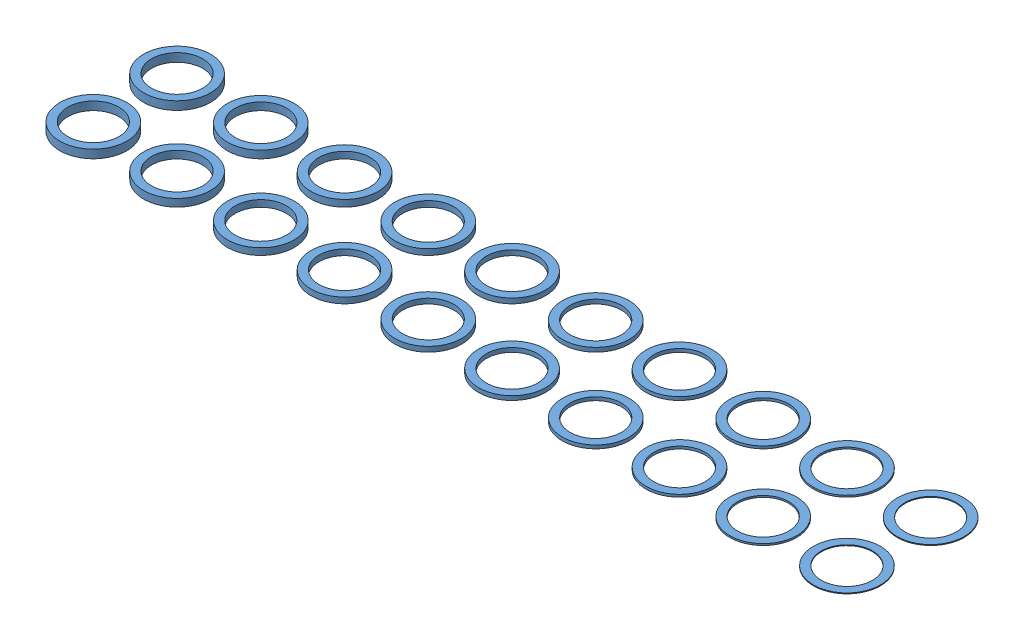
SolidWorks assembly Antrieb-Passscheibe, configuration Standard. Lengths in mm.
Overall size (98 1 18).
20 component instances, 1 part files, 3 mates.
Components (placement in the parent):
- Antrieb-Passscheibe-1: Antrieb-Passscheibe [T=1] x (1 0 0) z (0 -1 0) size (8 8 1)
- Antrieb-Passscheibe-2: Antrieb-Passscheibe [T=0,9] at (10 0 0) x (1 0 0) z (0 -1 0) size (8 8 0.9)
- Antrieb-Passscheibe-3: Antrieb-Passscheibe [T=0,8] at (20 0 0) x (1 0 0) z (0 -1 0) size (8 8 0.8)
- Antrieb-Passscheibe-4: Antrieb-Passscheibe [T=0,7] at (30 0 0) x (1 0 0) z (0 -1 0) size (8 8 0.7)
- Antrieb-Passscheibe-5: Antrieb-Passscheibe [T=0,6] at (40 0 0) x (1 0 0) z (0 -1 0) size (8 8 0.6)
- Antrieb-Passscheibe-6: Antrieb-Passscheibe [T=0,5] at (50 0 0) x (1 0 0) z (0 -1 0) size (8 8 0.5)
- Antrieb-Passscheibe-7: Antrieb-Passscheibe [T=0,4] at (60 0 0) x (1 0 0) z (0 -1 0) size (8 8 0.4)
- Antrieb-Passscheibe-8: Antrieb-Passscheibe [T=0,3] at (70 0 0) x (1 0 0) z (0 -1 0) size (8 8 0.3)
- Antrieb-Passscheibe-9: Antrieb-Passscheibe [T=0,2] at (80 0 0) x (1 0 0) z (0 -1 0) size (8 8 0.2)
- Antrieb-Passscheibe-10: Antrieb-Passscheibe [T=0,1] at (90 0 0) x (1 0 0) z (0 -1 0) size (8 8 0.1)
- Antrieb-Passscheibe-11: Antrieb-Passscheibe [T=0,6] at (40 0 -10) x (1 0 0) z (0 -1 0) size (8 8 0.6)
- Antrieb-Passscheibe-12: Antrieb-Passscheibe [T=0,4] at (60 0 -10) x (1 0 0) z (0 -1 0) size (8 8 0.4)
- Antrieb-Passscheibe-13: Antrieb-Passscheibe [T=0,5] at (50 0 -10) x (1 0 0) z (0 -1 0) size (8 8 0.5)
- Antrieb-Passscheibe-14: Antrieb-Passscheibe [T=0,1] at (90 0 -10) x (1 0 0) z (0 -1 0) size (8 8 0.1)
- Antrieb-Passscheibe-15: Antrieb-Passscheibe [T=0,2] at (80 0 -10) x (1 0 0) z (0 -1 0) size (8 8 0.2)
- Antrieb-Passscheibe-16: Antrieb-Passscheibe [T=0,3] at (70 0 -10) x (1 0 0) z (0 -1 0) size (8 8 0.3)
- Antrieb-Passscheibe-17: Antrieb-Passscheibe [T=0,7] at (30 0 -10) x (1 0 0) z (0 -1 0) size (8 8 0.7)
- Antrieb-Passscheibe-18: Antrieb-Passscheibe [T=0,8] at (20 0 -10) x (1 0 0) z (0 -1 0) size (8 8 0.8)
- Antrieb-Passscheibe-19: Antrieb-Passscheibe [T=1] at (0 0 -10) x (1 0 0) z (0 -1 0) size (8 8 1)
- Antrieb-Passscheibe-20: Antrieb-Passscheibe [T=0,9] at (10 0 -10) x (1 0 0) z (0 -1 0) size (8 8 0.9)
Mates (geometry in assembly coordinates):
- Deckungsgleich4: coincident anti-aligned: plane of Antrieb-Passscheibe-1 through (0 0 0) normal (0 -1 0); plane of assembly through (0 0 0) normal (0 1 0)
- Deckungsgleich5: coincident aligned: plane of Antrieb-Passscheibe-1; plane of assembly through (0 0 0) normal (1 0 0)
- Deckungsgleich6: coincident aligned: plane of Antrieb-Passscheibe-1 through (0 0 0) normal (0 0 1); plane of assembly through (0 0 0) normal (0 0 1)
